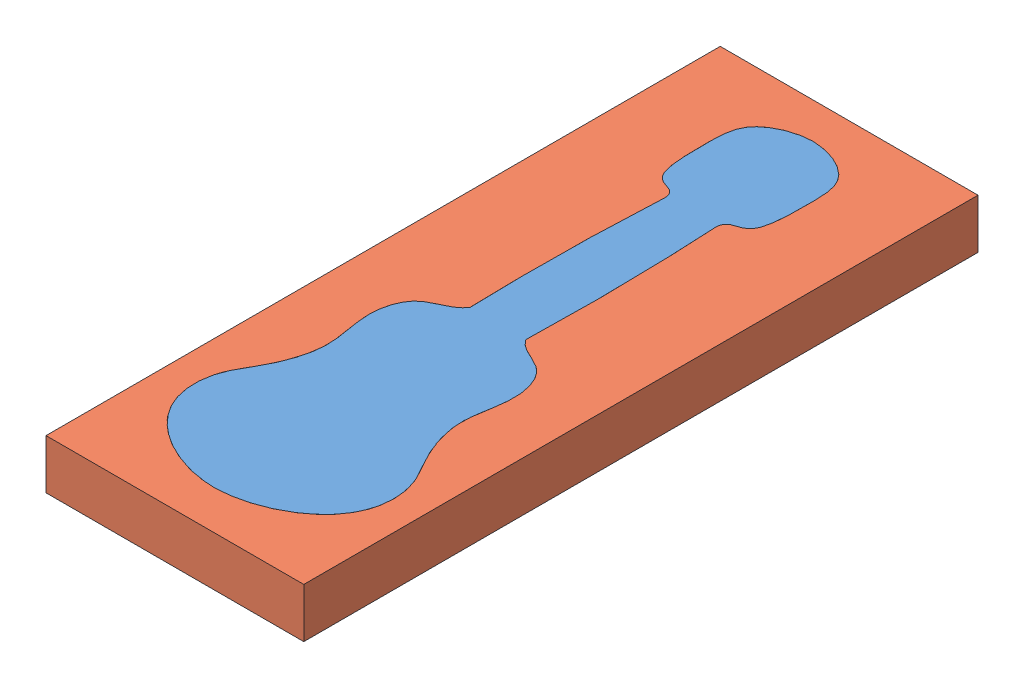
SolidWorks assembly UkiAssembly, configuration Default. Lengths in mm.
Overall size (260 533.06 696.91).
2 component instances, 2 part files, 4 mates.
Components (placement in the parent):
- uki-1: uki [Default] at origin size (226.91 533.06 696.91)
- negative-1: negative [Default] at (0 40 0) x (1 0 0) z (0 1 0) size (260 680 50)
Mates (geometry in assembly coordinates):
- InPlace1: in place: plane of uki-1 through (-86.1185 40 55.9488) normal (0 1 0); plane of negative-1 through (0 40 0) normal (0 1 0); moOrthogonalPlaneRef_w of uki-1 through (-86.1185 40 55.9488) normal (0 1 0); plane of negative-1 through (0 40 0) normal (0 0 -1); plane of uki-1 through (-86.1185 40 55.9488) normal (0 1 0); plane of negative-1 through (0 40 0) normal (1 0 0); plane of uki-1 through (-86.1185 40 55.9488) normal (0 1 0); unknown of negative-1
- Coincident1: coincident aligned: plane of uki-1; plane of negative-1
- Coincident2: coincident aligned: moOrthogonalPlaneRef_w of uki-1 through (0 40 0) normal (0 0 -1); plane of negative-1 through (0 40 0) normal (0 0 -1)
- Coincident3: coincident anti-aligned: moOrthogonalPlaneRef_w of uki-1 through (0 40 0) normal (-1 0 0); plane of negative-1 through (0 40 0) normal (1 0 0)
